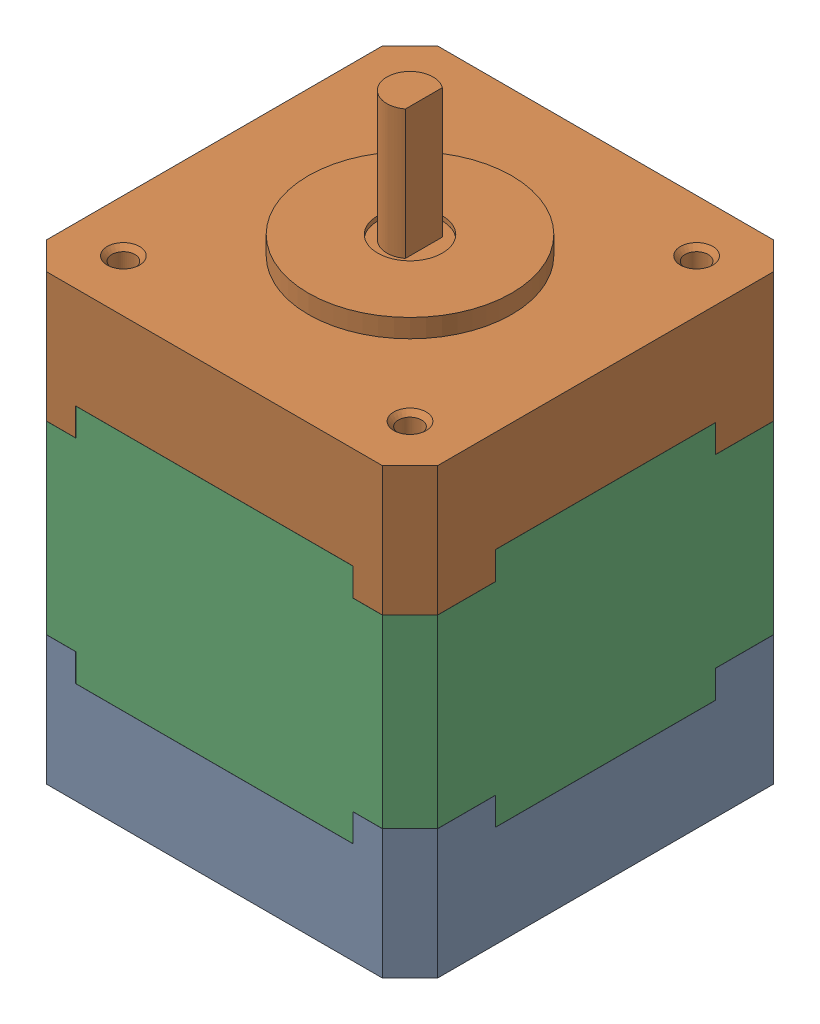
SolidWorks assembly Bolt Cutter Assembly, configuration Default. Lengths in mm.
Overall size (42.3 63.5 42.3).
3 component instances, 3 part files, 6 mates.
Components (placement in the parent):
- Bolt_Cutter_Sheet^V2-1: Bolt_Cutter_Sheet^V2 [Default] at (-25.4 529.1087 669.2587) (suppressed, hidden)
- L-bracket2motor mount-bolt-cutter-1: L-bracket2motor mount-bolt-cutter [Default] at (361.0329 356.3887 712.4387) x (-1 0 0) z (0 0 -1) (suppressed, hidden)
- stepper motor-1: stepper motor [Default] at (336.7079 381.4137 687.0387) x (0 0 1) z (0 1 0) size (42.3 42.3 63.5)
Mates (geometry in assembly coordinates):
- Coincident35: coincident anti-aligned: plane of Bolt_Cutter_Sheet^V2-1 through (361.0329 529.1087 669.2587) normal (-1 0 0); plane of L-bracket2motor mount-bolt-cutter-1 through (361.0329 356.3887 661.6387) normal (1 0 0)
- Concentric7: concentric anti-aligned: cylinder of Bolt_Cutter_Sheet^V2-1 through (361.0329 416.0787 687.0387) axis (1 0 0) radius 3.302; cylinder of L-bracket2motor mount-bolt-cutter-1 through (361.0329 416.0787 687.0387) axis (-1 0 0) radius 3.302
- Concentric8: concentric anti-aligned: cylinder of Bolt_Cutter_Sheet^V2-1 through (361.0329 369.0887 687.0387) axis (1 0 0) radius 3.302; cylinder of L-bracket2motor mount-bolt-cutter-1 through (361.0329 369.0887 687.0387) axis (-1 0 0) radius 3.302
- Concentric11: concentric aligned: cylinder of L-bracket2motor mount-bolt-cutter-1 through (352.2079 356.3887 671.5387) axis (0 1 0) radius 1.5; cylinder of stepper motor-1 through (352.2079 429.4137 671.5387) axis (0 1 0) radius 1.25
- Coincident54: coincident anti-aligned: plane of L-bracket2motor mount-bolt-cutter-1 through (315.5579 429.4137 661.6387) normal (0 -1 0); plane of stepper motor-1 through (357.8579 429.4137 708.1887) normal (0 1 0)
- Concentric12: concentric anti-aligned: cylinder of L-bracket2motor mount-bolt-cutter-1 through (336.7079 356.3887 687.0387) axis (0 1 0) radius 3; cylinder of stepper motor-1 through (336.7079 444.9137 687.0387) axis (0 -1 0) radius 2.5
